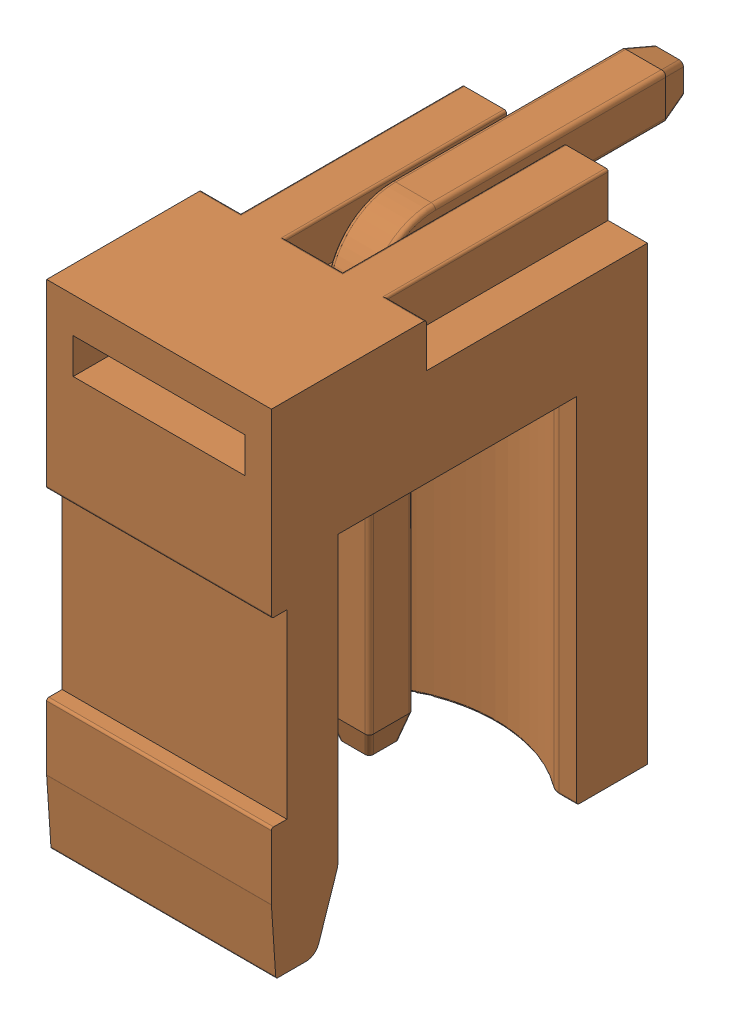
SolidWorks assembly KF2EDGK-1P_H, configuration 默认. Lengths in mm.
Overall size (5.08 11.3 11.5).
2 component instances, 2 part files, 0 mates.
Components (placement in the parent):
- LOGO横_-_0.5MM-1: LOGO横_-_0.5MM [默认] at (0.513 -1.4708 0) x (-1 0 0) z (0 0 -1) size (1.35 0.5 0.02)
- KF2EDGK-1P_H-1: KF2EDGK-1P_H [默认] at origin size (5.08 11.3 11.5)
